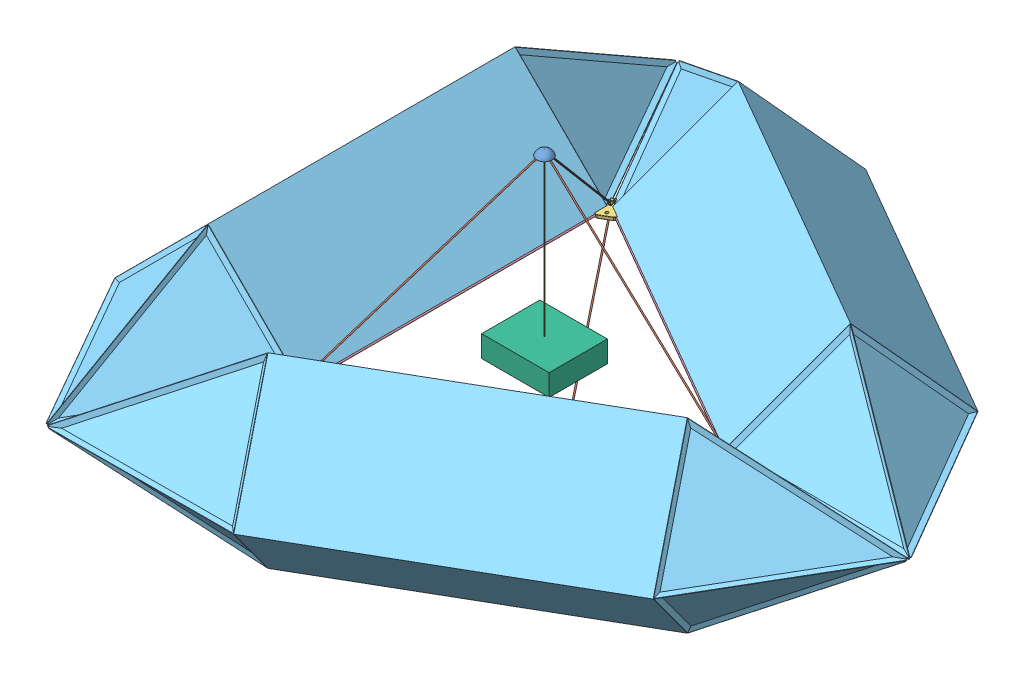
SolidWorks assembly AssemblageNEW, configuration Défaut. Lengths in mm.
Overall size (2234.94 1124.01 2580.68).
20 component instances, 8 part files, 24 mates.
Components (placement in the parent):
- Bout-1: Bout [Défaut] x (1 0 0) z (0 1 0) size (50 50 18)
- tigeCarboneCreux4mm-1: tigeCarboneCreux4mm [Défaut] at (588.7397 -536.0087 0) x (0.567696 0.608779 -0.554175) z (-0.731354 0.681998 0) size (4 4 800)
- pièceTriangle-1: pièceTriangle [Défaut] at (594.9989 -550.0203 0) x (-1 0 0) z (0 1 0) size (74.28 64.25 50.33)
- tigeCarboneCreux6mm-1: tigeCarboneCreux6mm [Défaut] at (-266.5215 -545.0203 494.1422) x (0.491313 -0.185599 0.850979) z (0.866025 0 -0.5) size (6 6 956.16)
- tigeCarboneCreux6mm-2: tigeCarboneCreux6mm [Défaut] at (561.2004 -545.0203 -16.2567) x (0.491313 -0.185599 -0.850979) z (-0.866025 0 -0.5) size (6 6 956.16)
- tigeCarboneCreux6mm-3: tigeCarboneCreux6mm [Défaut] at (-294.6789 -545.0203 -477.8855) x (-0.982626 -0.185599 0) z (0 0 1) size (6 6 956.16)
- pièceTriangle-2: pièceTriangle [Défaut] at (-297.4994 -550.0203 -515.2841) x (0.5 0 0.866025) z (0 1 0) size (74.28 64.25 50.33)
- pièceTriangle-3: pièceTriangle [Défaut] at (-297.4994 -550.0203 515.2841) x (0.5 0 -0.866025) z (0 1 0) size (74.28 64.25 50.33)
- tigeCarboneCreux4mm-2: tigeCarboneCreux4mm [Défaut] at (-294.3699 -536.0087 -509.8636) x (-0.763777 0.608779 -0.214551) z (0.365677 0.681998 0.633371) size (4 4 800)
- tigeCarboneCreux4mm-3: tigeCarboneCreux4mm [Défaut] at (-294.3699 -536.0087 509.8636) x (0.196082 0.608779 0.768726) z (0.365677 0.681998 -0.633371) size (4 4 800)
- tigeCarboneCreux4mm-4: tigeCarboneCreux4mm [Défaut] at (2.6439 -1098.5444 0) x (0.301513 -0.323333 0.896965) z (0.731354 0.681998 0) size (4 4 800)
- tigeCarboneCreux4mm-5: tigeCarboneCreux4mm [Défaut] at (-1.3219 -1098.5444 -2.2897) x (0.626038 -0.323333 -0.7096) z (-0.365677 0.681998 -0.633371) size (4 4 800)
- tigeCarboneCreux4mm-6: tigeCarboneCreux4mm [Défaut] at (-1.3219 -1098.5444 2.2897) x (-0.927551 -0.323333 -0.187364) z (-0.365677 0.681998 0.633371) size (4 4 800)
- Bout-2: Bout [Défaut] at (0 -1088.0098 0) x (-0.5 0 -0.866025) z (0 -1 0) size (50 50 18)
- BALLON-1: BALLON [Défaut] at (-134.9721 -240.9644 765.8215) x (0.866025 0 -0.5) z (-0.353553 -0.707107 -0.612372) size (2044.4 430 430)
- BALLON-2: BALLON [Défaut] at (730.7069 -240.9644 -266.0215) x (-0.866025 0 -0.5) z (-0.353553 -0.707107 0.612372) size (2044.4 430 430)
- BALLON-3: BALLON [Défaut] at (-595.7348 -240.9644 -499.8) x (0 0 1) z (0.707107 -0.707107 0) size (2044.4 430 430)
- Pièce1^AssemblageNEW-1: Pièce1^AssemblageNEW [Défaut] at origin (virtual)
- Drone-1: Drone [Défaut] at (110 -580 95) x (1 0 0) z (0 1 0) size (220 190 70)
- Corde-1: Corde [Défaut] at (0 -1088.0098 0) x (0.563501 0 0.826115) z (0 1 0) size (3 3 1088.1)
Mates (geometry in assembly coordinates):
- Coïncidente1: coincident anti-aligned: plane of Bout-1 through (0 0 0) normal (0 0 -1); plane of assembly through (0 0 0) normal (0 0 1)
- Coïncidente2: coincident anti-aligned: plane of Bout-1 through (0 0 0) normal (0 -1 0); plane of assembly through (0 0 0) normal (0 1 0)
- Coïncidente3: coincident aligned: plane of Bout-1; plane of assembly through (0 0 0) normal (1 0 0)
- Coaxiale1: concentric anti-aligned: cylinder of Bout-1 through (0 13 0) axis (-0.731354 0.681998 0) radius 2.15; cylinder of tigeCarboneCreux4mm-1 through (3.6568 9.59 0) axis (0.731354 -0.681998 0) radius 2
- Coïncidente4: coincident anti-aligned: plane of Bout-1 through (3.6568 9.59 0) normal (0.731354 -0.681998 0); plane of tigeCarboneCreux4mm-1 through (3.6568 9.59 0) normal (-0.731354 0.681998 0)
- Coaxiale2: concentric anti-aligned: cylinder of tigeCarboneCreux4mm-1 through (3.6568 9.59 0) axis (0.731354 -0.681998 0) radius 2; cylinder of pièceTriangle-1 through (588.7397 -536.0087 0) axis (-0.731354 0.681998 0) radius 2.15
- Coïncidente6: coincident anti-aligned: plane of Bout-1 through (0 0 0) normal (0 0 -1); plane of pièceTriangle-1
- Coaxiale3: concentric anti-aligned: cylinder of tigeCarboneCreux4mm-1 through (3.6568 9.59 0) axis (0.731354 -0.681998 0) radius 2; cylinder of pièceTriangle-1 through (588.7397 -536.0087 0) axis (-0.731354 0.681998 0) radius 2.15
- Coaxiale5: concentric aligned: cylinder of pièceTriangle-1 through (561.5373 -545.0203 16.0622) axis (-0.866025 0 0.5) radius 3.15; cylinder of tigeCarboneCreux6mm-1 through (561.5373 -545.0203 16.0622) axis (-0.866025 0 0.5) radius 3
- Coïncidente9: coincident anti-aligned: plane of pièceTriangle-1 through (561.5373 -545.0203 16.0622) normal (-0.866025 0 0.5); plane of tigeCarboneCreux6mm-1 through (561.5373 -545.0203 16.0622) normal (0.866025 0 -0.5)
- Coaxiale6: concentric aligned: cylinder of pièceTriangle-1 through (587.7269 -552.9457 0) axis (-0.731354 -0.681998 0) radius 2.15; cylinder of tigeCarboneCreux4mm-4 through (587.7269 -552.9457 0) axis (-0.731354 -0.681998 0) radius 2
- Coïncidente10: coincident anti-aligned: plane of pièceTriangle-1 through (587.7269 -552.9457 0) normal (-0.731354 -0.681998 0); plane of tigeCarboneCreux4mm-4 through (587.7269 -552.9457 0) normal (0.731354 0.681998 0)
- Coïncidente11: coincident anti-aligned: plane of tigeCarboneCreux4mm-1 through (588.7397 -536.0087 0) normal (0.731354 -0.681998 0); plane of pièceTriangle-1 through (588.7397 -536.0087 0) normal (-0.731354 0.681998 0)
- Coaxiale7: concentric aligned: cylinder of tigeCarboneCreux4mm-5 through (-293.8634 -552.9457 -508.9864) axis (0.365677 -0.681998 0.633371) radius 2; cylinder of Bout-2 through (0 -1101.0098 0) axis (0.365677 -0.681998 0.633371) radius 2.15
- Coaxiale8: concentric aligned: cylinder of tigeCarboneCreux4mm-6 through (-293.8634 -552.9457 508.9864) axis (0.365677 -0.681998 -0.633371) radius 2; cylinder of Bout-2 through (0 -1101.0098 0) axis (0.365677 -0.681998 -0.633371) radius 2.15
- Angle2: planar angle = 2.356194 rad aligned: plane of BALLON-1; plane of pièceTriangle-1 through (594.9989 -550.0203 0) normal (0 1 0)
- Coïncidente19: coincident: cylinder of tigeCarboneCreux6mm-1 through (561.5373 -545.0203 16.0622) axis (-0.866025 0 0.5) radius 3; line of BALLON-1 through (-287 -545.0203 502.5014) axis (0.866025 0 -0.5)
- Coïncidente22: coincident: plane of BALLON-1; point of assembly
- Coïncidente23: coincident: axis of tigeCarboneCreux6mm-3 through (-294.6789 -545.0203 478.2745) axis (0 0 -1); plane of BALLON-1
- Coïncidente24: coincident anti-aligned: plane of Bout-2 through (0 -1088.0098 0) normal (0 1 0); plane of Corde-1 through (0 -1088.0098 0) normal (0 -1 0)
- Coaxiale9: concentric anti-aligned: circle of Bout-2; circle of Corde-1
- Coaxiale10: concentric anti-aligned: circle of Drone-1; cylinder of Corde-1 through (0 0.0902 0) axis (0 -1 0) radius 1.5
- Distance1: distance = 510 mm aligned: plane of Drone-1 through (110 -510 95) normal (0 1 0); plane of assembly through (0 0 0) normal (0 1 0)
- Parallèle3: parallel anti-aligned: plane of ? through (-110 -460 95) normal (-1 0 0)
